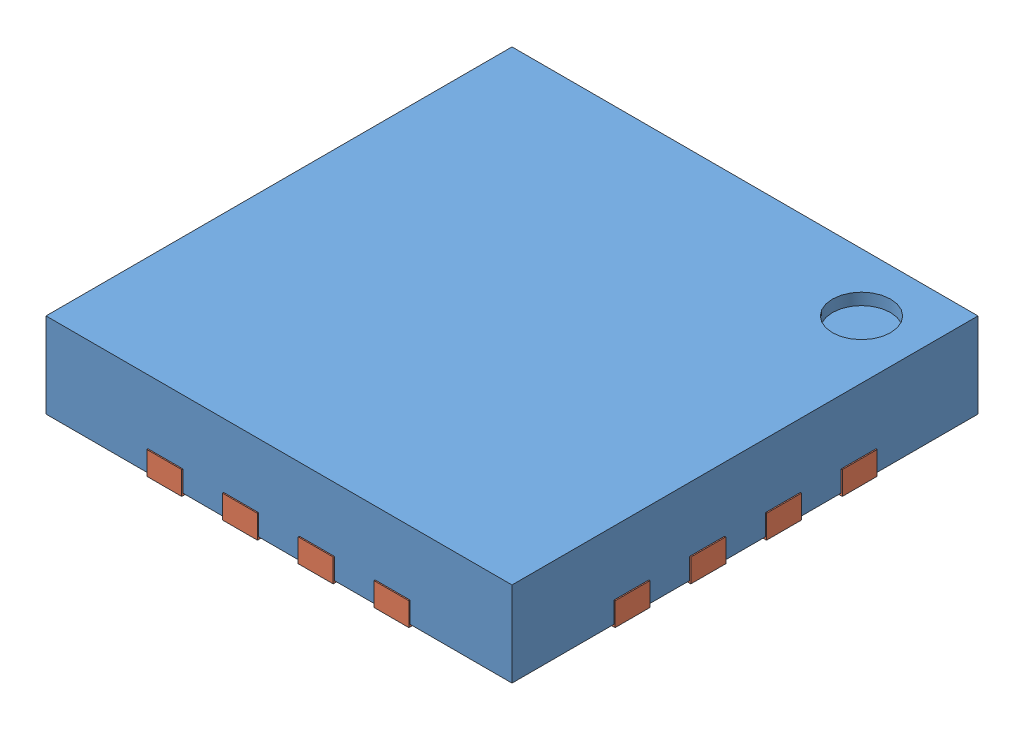
SolidWorks assembly CP-16-20, configuration Default. Lengths in mm.
Overall size (4.02 0.75 4.02).
18 component instances, 3 part files, 12 mates.
Components (placement in the parent):
- Body-1: Body [Default] at (0 0.02 0) size (4 0.73 4)
- P-1: P [Default] at (-1.805 0 -0.975) size (0.41 0.2 0.3)
- P-2: P [Default] at (-1.805 0 -0.325) size (0.41 0.2 0.3)
- P-3: P [Default] at (-1.805 0 0.325) size (0.41 0.2 0.3)
- P-4: P [Default] at (-1.805 0 0.975) size (0.41 0.2 0.3)
- P-5: P [Default] at (1.805 0 -0.975) x (-1 0 0) z (0 0 -1) size (0.41 0.2 0.3)
- P-6: P [Default] at (1.805 0 -0.325) x (-1 0 0) z (0 0 -1) size (0.41 0.2 0.3)
- P-7: P [Default] at (1.805 0 0.325) x (-1 0 0) z (0 0 -1) size (0.41 0.2 0.3)
- P-8: P [Default] at (1.805 0 0.975) x (-1 0 0) z (0 0 -1) size (0.41 0.2 0.3)
- P-9: P [Default] at (-0.975 0 1.805) x (0 0 -1) z (1 0 0) size (0.41 0.2 0.3)
- P-10: P [Default] at (-0.325 0 1.805) x (0 0 -1) z (1 0 0) size (0.41 0.2 0.3)
- P-11: P [Default] at (0.325 0 1.805) x (0 0 -1) z (1 0 0) size (0.41 0.2 0.3)
- P-12: P [Default] at (0.975 0 1.805) x (0 0 -1) z (1 0 0) size (0.41 0.2 0.3)
- P-13: P [Default] at (-0.975 0 -1.805) x (0 0 1) z (-1 0 0) size (0.41 0.2 0.3)
- P-14: P [Default] at (-0.325 0 -1.805) x (0 0 1) z (-1 0 0) size (0.41 0.2 0.3)
- P-15: P [Default] at (0.325 0 -1.805) x (0 0 1) z (-1 0 0) size (0.41 0.2 0.3)
- P-16: P [Default] at (0.975 0 -1.805) x (0 0 1) z (-1 0 0) size (0.41 0.2 0.3)
- EP-1: EP [Default] at (0 0.2 0) x (0 0 -1) z (-1 0 0) size (2.35 0.2 2.35)
Mates (geometry in assembly coordinates):
- Coincident1: coincident: plane of Body-1 through (0 0.02 0) normal (0 0 1); plane of assembly through (0 0 0) normal (0 0 1)
- Coincident2: coincident: plane of Body-1 through (0 0.02 0) normal (1 0 0); plane of assembly through (0 0 0) normal (1 0 0)
- Distance1: distance = 0.02 mm: plane of assembly through (0 0 0) normal (0 1 0); plane of Body-1 through (0 0.02 0) normal (0 -1 0)
- Coincident4: coincident: plane of P-1 through (-1.805 0 -0.975) normal (0 -1 0); plane of assembly through (0 0 0) normal (0 1 0)
- Distance2: distance = 0.01 mm: plane of P-1 through (-2.01 0.2 -0.825) normal (-1 0 0); plane of Body-1 through (-2 0.75 2) normal (-1 0 0)
- Distance3: distance = 0.975 mm: plane of P-1 through (-1.805 0 -0.975) normal (0 0 1); plane of assembly through (0 0 0) normal (0 0 1)
- Coincident7: coincident: plane of P-9 through (-0.975 0 1.805) normal (0 -1 0); plane of assembly through (0 0 0) normal (0 1 0)
- Distance4: distance = 0.01 mm: plane of P-9 through (-0.825 0.2 2.01) normal (0 0 1); plane of Body-1 through (-2 0.75 2) normal (0 0 1)
- Distance5: distance = 0.975 mm: plane of P-9 through (-0.975 0 1.805) normal (1 0 0); plane of assembly through (0 0 0) normal (1 0 0)
- Coincident10: coincident: plane of EP-1 through (0 0 0) normal (0 -1 0); plane of assembly
- Coincident11: coincident: plane of EP-1 through (0 0.2 0) normal (0 0 -1); plane of assembly
- Coincident12: coincident: plane of EP-1 through (0 0.2 0) normal (-1 0 0); plane of assembly
